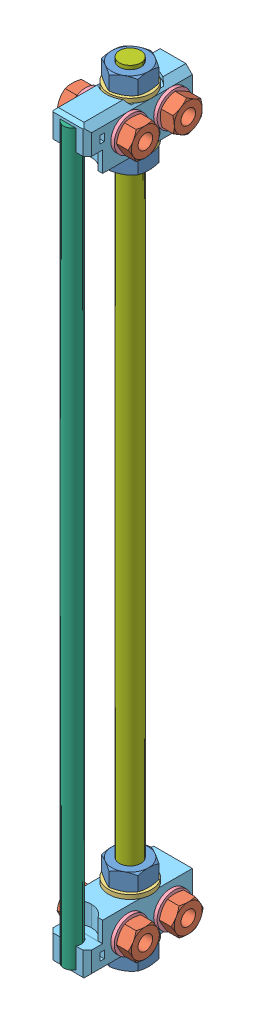
SolidWorks assembly Assembly y-axis left side, configuration Valor predeterminado. Lengths in mm.
Overall size (34.2 365 53.48).
30 component instances, 7 part files, 12 mates.
Components (placement in the parent):
- Assembly y-corners-1: Assembly y-corners [Valor predeterminado] at (-49.2679 151.5842 11.7032) x (-1 0 0) z (0 0 1) size (34.2 40 50.08)
  - Nut DIN 934 - M10-1: Nut DIN 934 - M10 [Valor predeterminado] at (-49.2679 6.8342 8.2968) x (0 -1 0) z (0.866025 0 0.5) size (8 17 19.63)
  - Nut DIN 934 - M8-1: Nut DIN 934 - M8 [Valor predeterminado] at (-63.1179 -10.1658 -1.7032) x (1 0 0) z (0 0.527567 0.849514) size (6.5 13 15.01)
  - Washer DIN 125A - M10-1: Washer DIN 125A - M10 [Valor predeterminado] at (-49.2679 -19.1658 8.2968) x (0 -1 0) z (0.326363 0 0.945245) size (2 20 20)
  - Washer DIN 125A - M8-1: Washer DIN 125A - M8 [Valor predeterminado] at (-40.2679 -10.1658 -1.7032) x (1 0 0) z (0 -0.550558 0.834797) size (1.6 16 16)
  - Washer DIN 125A - M10-2: Washer DIN 125A - M10 [Valor predeterminado] at (-49.2679 2.8342 8.2968) x (0 -1 0) z (0.326363 0 0.945245) size (2 20 20)
  - Washer DIN 125A - M8-2: Washer DIN 125A - M8 [Valor predeterminado] at (-59.8679 -10.1658 -1.7032) x (1 0 0) z (0 0.106248 0.99434) size (1.6 16 16)
  - Nut DIN 934 - M10-2: Nut DIN 934 - M10 [Valor predeterminado] at (-49.2679 -25.1658 8.2968) x (0 -1 0) z (0.866025 0 0.5) size (8 17 19.63)
  - Washer DIN 125A - M8-3: Washer DIN 125A - M8 [Valor predeterminado] at (-59.8679 -10.1658 18.2968) x (1 0 0) z (0 0.258445 0.966026) size (1.6 16 16)
  - Washer DIN 125A - M8-4: Washer DIN 125A - M8 [Valor predeterminado] at (-40.2679 -10.1658 18.2968) x (1 0 0) z (0 -0.676712 0.736248) size (1.6 16 16)
  - Nut DIN 934 - M8-2: Nut DIN 934 - M8 [Valor predeterminado] at (-63.1179 -10.1658 18.2968) x (1 0 0) z (0 0.866025 0.5) size (6.5 13 15.01)
  - Nut DIN 934 - M8-3: Nut DIN 934 - M8 [Valor predeterminado] at (-35.4179 -10.1658 18.2968) x (1 0 0) z (0 0.866025 0.5) size (6.5 13 15.01)
  - Nut DIN 934 - M8-4: Nut DIN 934 - M8 [Valor predeterminado] at (-35.4179 -10.1658 -1.7032) size (6.5 13 15.01)
  - y-corners-2: y-corners [Valor predeterminado] at (-49.2679 0.8342 -11.7032) size (18 22 49)
- Smooth Rod - 8 x 340-1: Smooth Rod - 8 x 340 [Valor predeterminado] at (0 0 47) x (0.46396 0 0.885856) z (0 -1 0) size (8 8 340)
- Assembly y-corners-2: Assembly y-corners [Valor predeterminado] at (49.2679 -151.5842 11.7032) size (34.2 40 50.08)
  - Nut DIN 934 - M10-1: Nut DIN 934 - M10 [Valor predeterminado] at (-49.2679 6.8342 8.2968) x (0 -1 0) z (0.866025 0 0.5) size (8 17 19.63)
  - Nut DIN 934 - M8-1: Nut DIN 934 - M8 [Valor predeterminado] at (-63.1179 -10.1658 -1.7032) x (1 0 0) z (0 0.527567 0.849514) size (6.5 13 15.01)
  - Washer DIN 125A - M10-1: Washer DIN 125A - M10 [Valor predeterminado] at (-49.2679 -19.1658 8.2968) x (0 -1 0) z (0.326363 0 0.945245) size (2 20 20)
  - Washer DIN 125A - M8-1: Washer DIN 125A - M8 [Valor predeterminado] at (-40.2679 -10.1658 -1.7032) x (1 0 0) z (0 -0.550558 0.834797) size (1.6 16 16)
  - Washer DIN 125A - M10-2: Washer DIN 125A - M10 [Valor predeterminado] at (-49.2679 2.8342 8.2968) x (0 -1 0) z (0.326363 0 0.945245) size (2 20 20)
  - Washer DIN 125A - M8-2: Washer DIN 125A - M8 [Valor predeterminado] at (-59.8679 -10.1658 -1.7032) x (1 0 0) z (0 0.106248 0.99434) size (1.6 16 16)
  - Nut DIN 934 - M10-2: Nut DIN 934 - M10 [Valor predeterminado] at (-49.2679 -25.1658 8.2968) x (0 -1 0) z (0.866025 0 0.5) size (8 17 19.63)
  - Washer DIN 125A - M8-3: Washer DIN 125A - M8 [Valor predeterminado] at (-59.8679 -10.1658 18.2968) x (1 0 0) z (0 0.258445 0.966026) size (1.6 16 16)
  - Washer DIN 125A - M8-4: Washer DIN 125A - M8 [Valor predeterminado] at (-40.2679 -10.1658 18.2968) x (1 0 0) z (0 -0.676712 0.736248) size (1.6 16 16)
  - Nut DIN 934 - M8-2: Nut DIN 934 - M8 [Valor predeterminado] at (-63.1179 -10.1658 18.2968) x (1 0 0) z (0 0.866025 0.5) size (6.5 13 15.01)
  - Nut DIN 934 - M8-3: Nut DIN 934 - M8 [Valor predeterminado] at (-35.4179 -10.1658 18.2968) x (1 0 0) z (0 0.866025 0.5) size (6.5 13 15.01)
  - Nut DIN 934 - M8-4: Nut DIN 934 - M8 [Valor predeterminado] at (-35.4179 -10.1658 -1.7032) size (6.5 13 15.01)
  - y-corners-2: y-corners [Valor predeterminado] at (-49.2679 0.8342 -11.7032) size (18 22 49)
- Threaded Rod DIN 975 - M10 x 365-2: Threaded Rod DIN 975 - M10 x 365 [Valor predeterminado] at (0 0 20) x (-0.687133 0 -0.726531) z (0 1 0) size (10 10 365)
Mates (geometry in assembly coordinates):
- Coincidente5: coincident: plane of ? through (0 0 71.2486) normal (0 -1 0); plane of ? through (0 0 44.2486) normal (0 1 0)
- Coincidente8: coincident: plane of ? through (0 0 71.2486) normal (0 -1 0); plane of assembly through (0 0 0) normal (0 1 0)
- Coincidente9: coincident: line of ? through (0 -170 71.2486) axis (0 1 0)
- Coincidente10: coincident: plane of ? through (0 -170 71.2486) normal (0 -1 0); plane of ? through (0 -170 71.2486) normal (0 1 0)
- Concêntrico1: concentric: cylinder of ? through (0 -170 71.2486) axis (0 1 0) radius 4; cylinder of ? through (0 -170 71.2486) axis (0 1 0) radius 4.2
- Coincidente11: coincident: plane of ? through (0 -150.75 24.2486) normal (1 0 0); plane of assembly through (0 0 0) normal (1 0 0)
- Coincidente13: coincident: plane of ? through (0 -170 71.2486) normal (0 -1 0); plane of ? through (0 -170 71.2486) normal (0 1 0)
- Concêntrico2: concentric: cylinder of ? through (0 -180.75 44.2486) axis (0 1 0) radius 4.25; cylinder of ? through (0 182.5 44.2486) axis (0 -1 0) radius 5
- Coincidente14: coincident: plane of ? through (0 170 71.2486) normal (0 -1 0); plane of ? through (0 170 71.2486) normal (0 1 0)
- Concêntrico3: concentric: cylinder of ? through (0 170 71.2486) axis (0 -1 0) radius 4.2; cylinder of ? through (0 -170 71.2486) axis (0 1 0) radius 4
- Coincidente15: coincident: plane of ? through (0 150.75 24.2486) normal (-1 0 0)
- Coincidente16: coincident: plane of assembly; plane of Assembly y-corners-2/y-corners-2 through (-9 -172.75 0) normal (0 0 -1); plane of assembly
